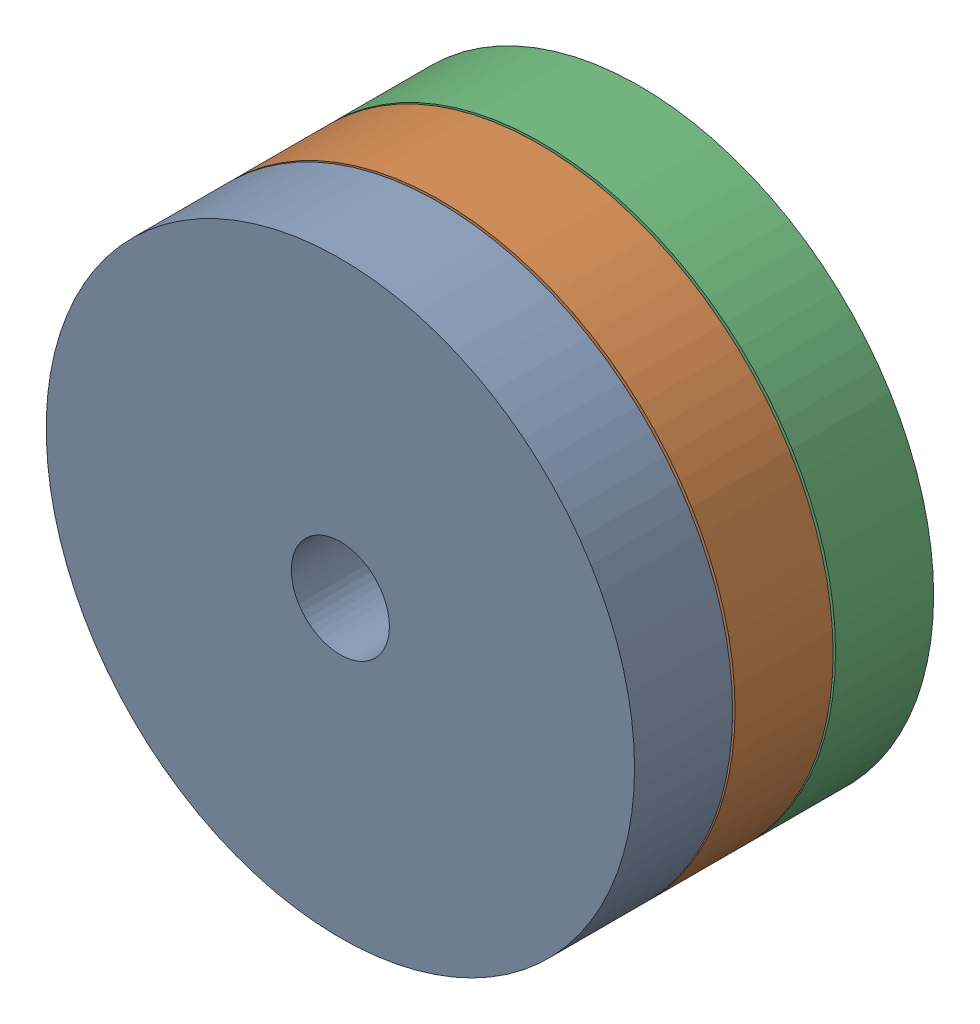
SolidWorks assembly Produit4, configuration Default. Lengths in mm.
Overall size (120 120 61).
3 component instances, 1 part files, 0 mates.
Components (placement in the parent):
- Part_Gateau3-1: Part_Gateau3 [Default] at (0 0 41) size (120 120 20)
- Part_Gateau3-2: Part_Gateau3 [Default] at (0 0 20.5) size (120 120 20)
- Part_Gateau3-3: Part_Gateau3 [Default] at origin size (120 120 20)
